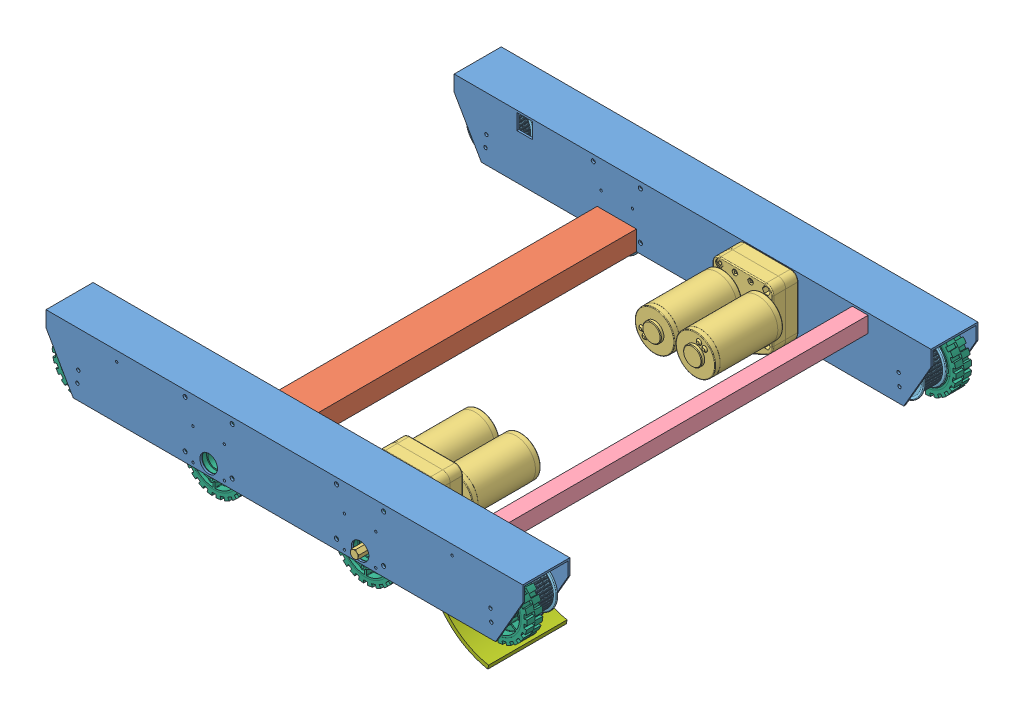
SolidWorks assembly 2016 Chassis 2.0, configuration Default. Lengths in mm.
Overall size (785.57 183.38 755.73).
31 component instances, 7 part files, 31 mates.
Components (placement in the parent):
- 3x4x31_C_channel-1: 3x4x31_C_channel [Default] at (380.7158 380.5786 558.1087) size (771.41 101.6 76.2)
- 3x4x31_C_channel-2: 3x4x31_C_channel [Default] at (380.7158 380.5786 1218.5087) x (-1 0 0) z (0 0 -1) size (771.41 101.6 76.2)
- Flanigon-1: Flanigon [Default] at (258.2154 361.6786 888.3087) size (63.5 31.75 584.2)
- Gearbox-1: Gearbox [Default] at (503.2277 381.6073 616.8462) x (-1 0 0) z (0 0 -1) size (141.64 114.27 241.64)
- Gearbox-2: Gearbox [Default] at (503.2216 381.613 1159.7712) x (1 -0.00015 0) z (0 0 1) size (141.64 114.27 241.64)
- 1x1_extrusion-1: 1x1_extrusion [Default] at (652.1216 415.5036 888.3087) size (25.4 25.4 730.25)
- Wheel_Pulley_Asm-1: Wheel_Pulley_Asm [Default] at (433.2033 352.7183 547.4613) x (0 0 1) z (0.923728 0.383049 0) size (68.56 101.6 101.6)
  - Double_Wide_Pulley-1: Double_Wide_Pulley [Default] at (-18.9345 -2.473 5.088) size (37.95 74.23 74.23)
  - 4 in HiGrip Wheel-1: 4 in HiGrip Wheel [Default] at (1.9518 29.3543 60.0417) x (1 0 0) z (0 0.000042 1) size (35.12 101.6 101.6)
- Wheel_Pulley_Asm-2: Wheel_Pulley_Asm [Default] at (644.1787 378.1183 547.4613) x (0 0 1) z (0.923728 0.383049 0) size (68.56 101.6 101.6)
  - Double_Wide_Pulley-1: Double_Wide_Pulley [Default] at (-18.9345 -2.473 5.088) size (37.95 74.23 74.23)
  - 4 in HiGrip Wheel-1: 4 in HiGrip Wheel [Default] at (1.9518 29.3543 60.0417) x (1 0 0) z (0 0.000042 1) size (35.12 101.6 101.6)
- Wheel_Pulley_Asm-3: Wheel_Pulley_Asm [Default] at (320.7903 315.3631 547.4613) x (0 0 1) z (-1 0 0) size (68.56 101.6 101.6)
  - Double_Wide_Pulley-1: Double_Wide_Pulley [Default] at (-18.9345 -2.473 5.088) size (37.95 74.23 74.23)
  - 4 in HiGrip Wheel-1: 4 in HiGrip Wheel [Default] at (1.9518 29.3543 60.0417) x (1 0 0) z (0 0.000042 1) size (35.12 101.6 101.6)
- Wheel_Pulley_Asm-4: Wheel_Pulley_Asm [Default] at (109.8149 340.7631 547.4613) x (0 0 1) z (-1 0 0) size (68.56 101.6 101.6)
  - Double_Wide_Pulley-1: Double_Wide_Pulley [Default] at (-18.9345 -2.473 5.088) size (37.95 74.23 74.23)
  - 4 in HiGrip Wheel-1: 4 in HiGrip Wheel [Default] at (1.9518 29.3543 60.0417) x (1 0 0) z (0 0.000042 1) size (35.12 101.6 101.6)
- Wheel_Pulley_Asm-5: Wheel_Pulley_Asm [Default] at (-15.3349 340.7631 1229.156) x (0 0 -1) z (1 0 0) size (68.56 101.6 101.6)
  - Double_Wide_Pulley-1: Double_Wide_Pulley [Default] at (-18.9345 -2.473 5.088) size (37.95 74.23 74.23)
  - 4 in HiGrip Wheel-1: 4 in HiGrip Wheel [Default] at (1.9518 29.3543 60.0417) x (1 0 0) z (0 0.000042 1) size (35.12 101.6 101.6)
- Wheel_Pulley_Asm-6: Wheel_Pulley_Asm [Default] at (195.6406 315.3631 1229.156) x (0 0 -1) z (1 0 0) size (68.56 101.6 101.6)
  - Double_Wide_Pulley-1: Double_Wide_Pulley [Default] at (-18.9345 -2.473 5.088) size (37.95 74.23 74.23)
  - 4 in HiGrip Wheel-1: 4 in HiGrip Wheel [Default] at (1.9518 29.3543 60.0417) x (1 0 0) z (0 0.000042 1) size (35.12 101.6 101.6)
- Wheel_Pulley_Asm-7: Wheel_Pulley_Asm [Default] at (440.6414 315.3631 1229.156) x (0 0 -1) z (1 0 0) size (68.56 101.6 101.6)
  - Double_Wide_Pulley-1: Double_Wide_Pulley [Default] at (-18.9345 -2.473 5.088) size (37.95 74.23 74.23)
  - 4 in HiGrip Wheel-1: 4 in HiGrip Wheel [Default] at (1.9518 29.3543 60.0417) x (1 0 0) z (0 0.000042 1) size (35.12 101.6 101.6)
- Wheel_Pulley_Asm-8: Wheel_Pulley_Asm [Default] at (651.6168 340.7631 1229.156) x (0 0 -1) z (1 0 0) size (68.56 101.6 101.6)
  - Double_Wide_Pulley-1: Double_Wide_Pulley [Default] at (-18.9345 -2.473 5.088) size (37.95 74.23 74.23)
  - 4 in HiGrip Wheel-1: 4 in HiGrip Wheel [Default] at (1.9518 29.3543 60.0417) x (1 0 0) z (0 0.000042 1) size (35.12 101.6 101.6)
- Ramp-1: Ramp [Default] at (702.7164 374.2437 1163.7181) size (82.86 60.43 127)
Mates (geometry in assembly coordinates):
- Concentric8: concentric anti-aligned: cylinder of 3x4x31_C_channel-1 through (283.6154 336.2786 596.2087) axis (0 0 1) radius 1.8986; cylinder of Flanigon-1 through (283.6154 336.2786 1180.4087) axis (0 0 -1) radius 3
- Concentric9: concentric anti-aligned: cylinder of 3x4x31_C_channel-1 through (232.8154 336.2786 596.2087) axis (0 0 1) radius 1.8986; cylinder of Flanigon-1 through (232.8154 336.2786 1180.4087) axis (0 0 -1) radius 3
- Coincident1: coincident anti-aligned: plane of 3x4x31_C_channel-1 through (766.4216 431.3786 596.2087) normal (0 0 1); plane of Flanigon-1 through (258.2154 361.6786 596.2087) normal (0 0 -1)
- Concentric10: concentric aligned: cylinder of 3x4x31_C_channel-2 through (232.8154 336.2786 1180.4087) axis (0 0 -1) radius 1.8986; cylinder of Flanigon-1 through (232.8154 336.2786 1180.4087) axis (0 0 -1) radius 3
- Concentric11: concentric aligned: cylinder of 3x4x31_C_channel-2 through (283.6154 336.2786 1180.4087) axis (0 0 -1) radius 1.8986; cylinder of Flanigon-1 through (283.6154 336.2786 1180.4087) axis (0 0 -1) radius 3
- Coincident2: coincident anti-aligned: plane of 3x4x31_C_channel-2 through (-4.9899 431.3786 1180.4087) normal (0 0 -1); plane of Flanigon-1 through (258.2154 361.6786 1180.4087) normal (0 0 1)
- Concentric16: concentric anti-aligned: cylinder of 3x4x31_C_channel-1 through (465.1277 345.4551 596.2087) axis (0 0 -1) radius 3.302; cylinder of Gearbox-1 through (465.1277 345.4551 628.5937) axis (0 0 1) radius 2.5146
- Concentric17: concentric anti-aligned: cylinder of 3x4x31_C_channel-1 through (465.1277 421.6551 596.2087) axis (0 0 -1) radius 3.302; cylinder of Gearbox-1 through (465.1277 421.6551 628.5937) axis (0 0 1) radius 2.5146
- Coincident3: coincident anti-aligned: plane of 3x4x31_C_channel-1 through (766.4216 431.3786 596.2087) normal (0 0 1); plane of Gearbox-1 through (472.7477 348.1419 596.2087) normal (0 0 -1)
- Concentric18: concentric anti-aligned: cylinder of 3x4x31_C_channel-2 through (541.3162 345.4551 1180.4087) axis (0 0 1) radius 3.302; cylinder of Gearbox-2 through (541.3162 345.4551 1148.0237) axis (0 0 -1) radius 2.5146
- Concentric19: concentric anti-aligned: cylinder of 3x4x31_C_channel-2 through (541.3277 421.6551 1180.4087) axis (0 0 1) radius 3.302; cylinder of Gearbox-2 through (541.3277 421.6551 1148.0237) axis (0 0 -1) radius 2.5146
- Coincident5: coincident anti-aligned: plane of 3x4x31_C_channel-2 through (-4.9899 431.3786 1180.4087) normal (0 0 -1); plane of Gearbox-2 through (533.6966 348.143 1180.4087) normal (0 0 1)
- Concentric20: concentric anti-aligned: cylinder of 3x4x31_C_channel-2 through (652.1216 415.5036 1253.4337) axis (0 0 -1) radius 1.8986; cylinder of 1x1_extrusion-1 through (652.1216 415.5036 441.1417) axis (0 0 1) radius 2.0828
- Distance2: distance = 0 mm anti-aligned: plane of 3x4x31_C_channel-2 through (-4.9899 428.2036 1253.4337) normal (0 0 -1); plane of 1x1_extrusion-1 through (652.1216 415.5036 1253.4337) normal (0 0 1)
- Coincident7: coincident anti-aligned: plane of 3x4x31_C_channel-2 through (-4.9899 428.2036 1183.5837) normal (0 -1 0); plane of 1x1_extrusion-1 through (639.4216 428.2036 1253.4337) normal (0 1 0)
- Concentric21: concentric aligned: cylinder of 3x4x31_C_channel-1 through (503.2162 347.2411 454.4767) axis (0 0 1) radius 14.2875; cylinder of Wheel_Pulley_Asm-1/Double_Wide_Pulley-1 through (503.2162 347.2411 564.8692) axis (0 0 1) radius 12.2555
- Distance3: distance = 0.7153 mm anti-aligned: plane of Wheel_Pulley_Asm-1/4 in HiGrip Wheel-1 through (503.2171 347.2414 523.899) normal (0 0 -1); plane of 3x4x31_C_channel-1 through (766.4216 428.2036 523.1837) normal (0 0 1)
- Concentric22: concentric aligned: cylinder of 3x4x31_C_channel-1 through (714.1917 372.6411 454.4767) axis (0 0 1) radius 2.75; cylinder of Wheel_Pulley_Asm-2/Double_Wide_Pulley-1 through (714.1917 372.6411 564.8692) axis (0 0 1) radius 12.2555
- Distance4: distance = 0.7153 mm anti-aligned: plane of Wheel_Pulley_Asm-2/4 in HiGrip Wheel-1 through (714.1926 372.6414 523.899) normal (0 0 -1); plane of 3x4x31_C_channel-1 through (766.4216 428.2036 523.1837) normal (0 0 1)
- Concentric23: concentric aligned: cylinder of 3x4x31_C_channel-1 through (258.2154 347.2411 454.4767) axis (0 0 1) radius 14.2875; cylinder of Wheel_Pulley_Asm-3/Double_Wide_Pulley-1 through (258.2154 347.2411 564.8692) axis (0 0 1) radius 12.2555
- Distance5: distance = 0.7153 mm anti-aligned: plane of Wheel_Pulley_Asm-3/4 in HiGrip Wheel-1 through (258.2144 347.2411 523.899) normal (0 0 -1); plane of 3x4x31_C_channel-1 through (766.4216 428.2036 523.1837) normal (0 0 1)
- Concentric24: concentric aligned: cylinder of 3x4x31_C_channel-1 through (47.24 372.6411 454.4767) axis (0 0 1) radius 2.75; cylinder of Wheel_Pulley_Asm-4/Double_Wide_Pulley-1 through (47.24 372.6411 564.8692) axis (0 0 1) radius 12.2555
- Distance6: distance = 0.7153 mm anti-aligned: plane of 3x4x31_C_channel-1 through (766.4216 428.2036 523.1837) normal (0 0 1); plane of Wheel_Pulley_Asm-4/4 in HiGrip Wheel-1 through (47.239 372.6411 523.899) normal (0 0 -1)
- Concentric26: concentric aligned: cylinder of 3x4x31_C_channel-2 through (47.24 372.6411 1322.1407) axis (0 0 -1) radius 2.75; cylinder of Wheel_Pulley_Asm-5/Double_Wide_Pulley-1 through (47.24 372.6411 1211.7482) axis (0 0 -1) radius 12.2555
- Distance7: distance = 0.7153 mm anti-aligned: plane of Wheel_Pulley_Asm-5/4 in HiGrip Wheel-1 through (47.241 372.6411 1252.7184) normal (0 0 1); plane of 3x4x31_C_channel-2 through (-4.9899 428.2036 1253.4337) normal (0 0 -1)
- Concentric27: concentric aligned: cylinder of 3x4x31_C_channel-2 through (258.2154 347.2411 1322.1407) axis (0 0 -1) radius 14.2875; cylinder of Wheel_Pulley_Asm-6/Double_Wide_Pulley-1 through (258.2154 347.2411 1211.7482) axis (0 0 -1) radius 12.2555
- Distance8: distance = 0.7153 mm anti-aligned: plane of Wheel_Pulley_Asm-6/4 in HiGrip Wheel-1 through (258.2164 347.2411 1252.7184) normal (0 0 1); plane of 3x4x31_C_channel-2 through (-4.9899 428.2036 1253.4337) normal (0 0 -1)
- Concentric28: concentric aligned: cylinder of 3x4x31_C_channel-2 through (503.2162 347.2411 1322.1407) axis (0 0 -1) radius 14.2875; cylinder of Wheel_Pulley_Asm-7/Double_Wide_Pulley-1 through (503.2162 347.2411 1211.7482) axis (0 0 -1) radius 12.2555
- Distance9: distance = 0.7153 mm anti-aligned: plane of Wheel_Pulley_Asm-7/4 in HiGrip Wheel-1 through (503.2172 347.2411 1252.7184) normal (0 0 1); plane of 3x4x31_C_channel-2 through (-4.9899 428.2036 1253.4337) normal (0 0 -1)
- Concentric29: concentric aligned: cylinder of 3x4x31_C_channel-2 through (714.1917 372.6411 1322.1407) axis (0 0 -1) radius 2.75; cylinder of Wheel_Pulley_Asm-8/Double_Wide_Pulley-1 through (714.1917 372.6411 1211.7482) axis (0 0 -1) radius 12.2555
- Distance10: distance = 0.7153 mm anti-aligned: plane of Wheel_Pulley_Asm-8/4 in HiGrip Wheel-1 through (714.1927 372.6411 1252.7184) normal (0 0 1); plane of 3x4x31_C_channel-2 through (-4.9899 428.2036 1253.4337) normal (0 0 -1)
